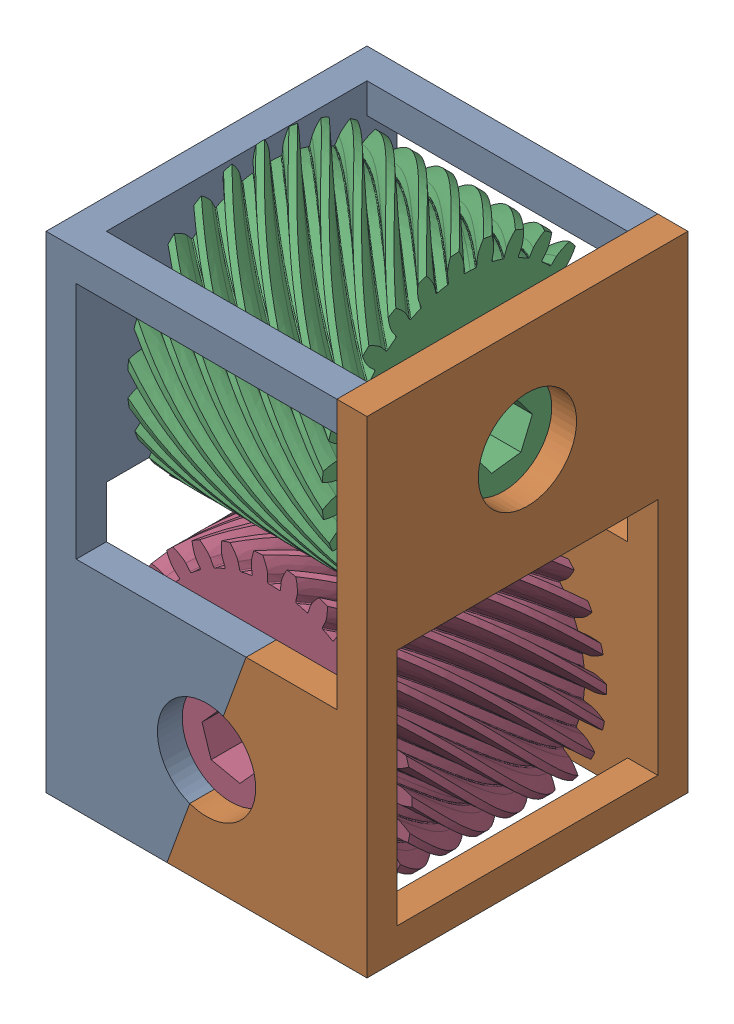
SolidWorks assembly gear box 90, configuration Default. Lengths in mm.
Overall size (95.24 160.1 84.39).
3 component instances, 2 part files, 5 mates.
Components (placement in the parent):
- Frame-1: Frame [Default] at origin size (83.82 127 83.82)
- Gear-1: Gear [Default] at (-25.4 98.6155 0) x (0 0.12451 -0.992218) z (1 0 0) size (75.56 75.64 71.12)
- Gear-2: Gear [Default] at (0 28.3845 -25.4) x (0.308168 -0.951332 0) z (0 0 1) size (75.56 75.64 71.12)
Mates (geometry in assembly coordinates):
- Width1: width anti-aligned: plane of Gear-1 through (25.4 99.6644 1.2751) normal (1 0 0); plane of Frame-1 through (-25.4 99.6644 1.2751) normal (-1 0 0); plane of Gear-1 through (34.036 0 34.036) normal (-1 0 0); plane of Frame-1 through (-34.036 0 -34.036) normal (1 0 0)
- Width2: width anti-aligned: plane of Frame-1 through (-41.91 127 -41.91) normal (0 0 -1); plane of Gear-2 through (-41.91 127 41.91) normal (0 0 1); plane of Frame-1 through (0 28.3845 35.56) normal (0 0 1); plane of Gear-2 through (0 28.3845 -35.56) normal (0 0 -1)
- Concentric6: concentric anti-aligned: cylinder of Frame-1 through (-41.91 98.6155 0) axis (1 0 0) radius 12.827; cylinder of Gear-1 through (35.56 98.6155 0) axis (-1 0 0) radius 12.7
- Concentric7: concentric anti-aligned: cylinder of Frame-1 through (0 28.3845 -41.91) axis (0 0 1) radius 12.827; cylinder of Gear-2 through (0 28.3845 35.56) axis (0 0 -1) radius 12.7
- Width3: width anti-aligned: plane of Frame-1 through (41.91 127 41.91) normal (1 0 0); plane of Gear-1 through (-41.91 127 41.91) normal (-1 0 0); plane of Frame-1 through (-25.4 98.6155 0) normal (-1 0 0); plane of Gear-1 through (25.4 98.6155 0) normal (1 0 0)
